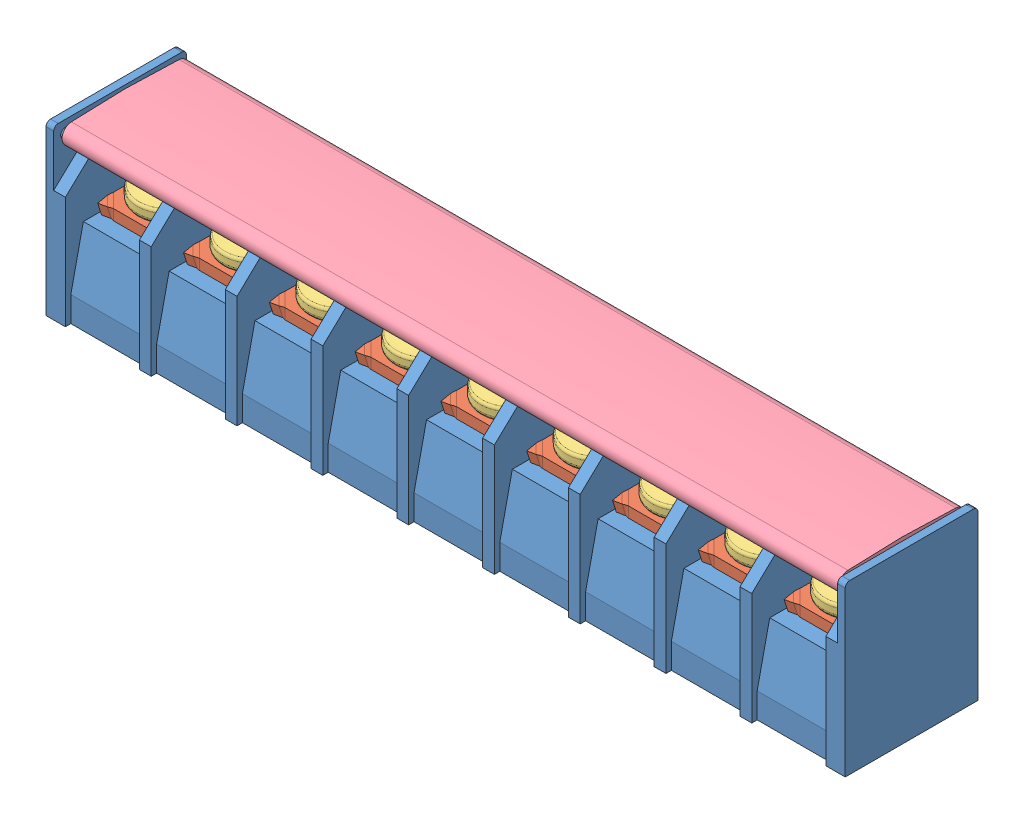
SolidWorks assembly Switchlab T14-EO33-09 Terminal Block, configuration Default. Lengths in mm.
Overall size (88.5 18.62 14.7).
20 component instances, 4 part files, 9 mates.
Components (placement in the parent):
- Body of Switchlab T14-EO33-09 Terminal Block-1: Body of Switchlab T14-EO33-09 Terminal Block [Default] at (-5.6384 -1.479 88.5) size (88.5 18.6 14.7)
- Clamp Plate of Switchlab T14-EO33-09 Terminal Block-1: Clamp Plate of Switchlab T14-EO33-09 Terminal Block [Default] at (-43.6384 9.0158 88.5) size (8.4 1.4 8.4)
- Philips-Drive Panhead Screw of Switchlab T14-EO33-09 Terminal Block-1: Philips-Drive Panhead Screw of Switchlab T14-EO33-09 Terminal Block [92000A151] at (-43.6384 3.0158 88.5) x (1 0 0) z (0 1 0) size (7 7 8.8)
- Philips-Drive Panhead Screw of Switchlab T14-EO33-09 Terminal Block-2: Philips-Drive Panhead Screw of Switchlab T14-EO33-09 Terminal Block [92000A151] at (-34.1384 3.0158 88.5) x (1 0 0) z (0 1 0) size (7 7 8.8)
- Philips-Drive Panhead Screw of Switchlab T14-EO33-09 Terminal Block-3: Philips-Drive Panhead Screw of Switchlab T14-EO33-09 Terminal Block [92000A151] at (-24.6384 3.0158 88.5) x (1 0 0) z (0 1 0) size (7 7 8.8)
- Philips-Drive Panhead Screw of Switchlab T14-EO33-09 Terminal Block-4: Philips-Drive Panhead Screw of Switchlab T14-EO33-09 Terminal Block [92000A151] at (-15.1384 3.0158 88.5) x (1 0 0) z (0 1 0) size (7 7 8.8)
- Philips-Drive Panhead Screw of Switchlab T14-EO33-09 Terminal Block-5: Philips-Drive Panhead Screw of Switchlab T14-EO33-09 Terminal Block [92000A151] at (-5.6384 3.0158 88.5) x (1 0 0) z (0 1 0) size (7 7 8.8)
- Philips-Drive Panhead Screw of Switchlab T14-EO33-09 Terminal Block-6: Philips-Drive Panhead Screw of Switchlab T14-EO33-09 Terminal Block [92000A151] at (3.8616 3.0158 88.5) x (1 0 0) z (0 1 0) size (7 7 8.8)
- Philips-Drive Panhead Screw of Switchlab T14-EO33-09 Terminal Block-7: Philips-Drive Panhead Screw of Switchlab T14-EO33-09 Terminal Block [92000A151] at (13.3616 3.0158 88.5) x (1 0 0) z (0 1 0) size (7 7 8.8)
- Philips-Drive Panhead Screw of Switchlab T14-EO33-09 Terminal Block-8: Philips-Drive Panhead Screw of Switchlab T14-EO33-09 Terminal Block [92000A151] at (22.8616 3.0158 88.5) x (1 0 0) z (0 1 0) size (7 7 8.8)
- Philips-Drive Panhead Screw of Switchlab T14-EO33-09 Terminal Block-9: Philips-Drive Panhead Screw of Switchlab T14-EO33-09 Terminal Block [92000A151] at (32.3616 3.0158 88.5) x (1 0 0) z (0 1 0) size (7 7 8.8)
- Clamp Plate of Switchlab T14-EO33-09 Terminal Block-2: Clamp Plate of Switchlab T14-EO33-09 Terminal Block [Default] at (-34.1384 9.0158 88.5) size (8.4 1.4 8.4)
- Clamp Plate of Switchlab T14-EO33-09 Terminal Block-3: Clamp Plate of Switchlab T14-EO33-09 Terminal Block [Default] at (-24.6384 9.0158 88.5) size (8.4 1.4 8.4)
- Clamp Plate of Switchlab T14-EO33-09 Terminal Block-4: Clamp Plate of Switchlab T14-EO33-09 Terminal Block [Default] at (-15.1384 9.0158 88.5) size (8.4 1.4 8.4)
- Clamp Plate of Switchlab T14-EO33-09 Terminal Block-5: Clamp Plate of Switchlab T14-EO33-09 Terminal Block [Default] at (-5.6384 9.0158 88.5) size (8.4 1.4 8.4)
- Clamp Plate of Switchlab T14-EO33-09 Terminal Block-6: Clamp Plate of Switchlab T14-EO33-09 Terminal Block [Default] at (3.8616 9.0158 88.5) size (8.4 1.4 8.4)
- Clamp Plate of Switchlab T14-EO33-09 Terminal Block-7: Clamp Plate of Switchlab T14-EO33-09 Terminal Block [Default] at (13.3616 9.0158 88.5) size (8.4 1.4 8.4)
- Clamp Plate of Switchlab T14-EO33-09 Terminal Block-8: Clamp Plate of Switchlab T14-EO33-09 Terminal Block [Default] at (22.8616 9.0158 88.5) size (8.4 1.4 8.4)
- Clamp Plate of Switchlab T14-EO33-09 Terminal Block-9: Clamp Plate of Switchlab T14-EO33-09 Terminal Block [Default] at (32.3616 9.0158 88.5) size (8.4 1.4 8.4)
- Cover for Switchlab T14-EO33-09 Terminal Block-1: Cover for Switchlab T14-EO33-09 Terminal Block [Default] at (-5.6384 17.141 88.3265) size (86 2.95 14)
Mates (geometry in assembly coordinates):
- Coincident1: coincident: plane of Body of Switchlab T14-EO33-09 Terminal Block-1 through (38.6116 7.621 93.865) normal (0 1 0); point of Clamp Plate of Switchlab T14-EO33-09 Terminal Block-1
- Coincident2: coincident: plane of Body of Switchlab T14-EO33-09 Terminal Block-1 through (38.6116 7.621 93.865) normal (0 1 0); point of Clamp Plate of Switchlab T14-EO33-09 Terminal Block-1
- Coincident3: coincident: plane of Body of Switchlab T14-EO33-09 Terminal Block-1 through (38.6116 7.621 93.865) normal (0 1 0); point of Clamp Plate of Switchlab T14-EO33-09 Terminal Block-1
- Concentric1: concentric aligned: cylinder of Body of Switchlab T14-EO33-09 Terminal Block-1 through (-43.6384 7.621 88.5) axis (0 1 0) radius 1.45; cylinder of Clamp Plate of Switchlab T14-EO33-09 Terminal Block-1 through (-43.6384 9.0158 88.5) axis (0 1 0) radius 1.85
- Concentric2: concentric aligned: cylinder of Clamp Plate of Switchlab T14-EO33-09 Terminal Block-1 through (-43.6384 9.0158 88.5) axis (0 1 0) radius 1.85; cylinder of Philips-Drive Panhead Screw of Switchlab T14-EO33-09 Terminal Block-1 through (-43.6384 3.0158 88.5) axis (0 1 0) radius 1.75
- Coincident4: coincident anti-aligned: plane of Clamp Plate of Switchlab T14-EO33-09 Terminal Block-1 through (-43.6384 9.0158 88.5) normal (0 1 0); plane of Philips-Drive Panhead Screw of Switchlab T14-EO33-09 Terminal Block-1 through (-43.6384 9.0158 88.5) normal (0 -1 0)
- Width1: width anti-aligned: plane of Cover for Switchlab T14-EO33-09 Terminal Block-1 through (37.3616 15.851 94.2279) normal (1 0 0); plane of Cover for Switchlab T14-EO33-09 Terminal Block-1 through (-48.6384 15.851 94.2279) normal (-1 0 0); plane of Body of Switchlab T14-EO33-09 Terminal Block-1 through (37.7616 16.621 95.35) normal (-1 0 0); plane of Body of Switchlab T14-EO33-09 Terminal Block-1 through (-49.0384 16.621 95.35) normal (1 0 0)
- Concentric3: concentric anti-aligned: cylinder of Body of Switchlab T14-EO33-09 Terminal Block-1 through (26.9616 15.851 82.425) axis (1 0 0) radius 0.5; cylinder of Cover for Switchlab T14-EO33-09 Terminal Block-1 through (37.3616 15.851 82.425) axis (-1 0 0) radius 0.6685
- Parallel1: parallel aligned: plane of Body of Switchlab T14-EO33-09 Terminal Block-1 through (26.9616 16.351 88.5) normal (0 1 0); plane of Cover for Switchlab T14-EO33-09 Terminal Block-1 through (-5.6384 17.141 88.3265) normal (0 1 0)
